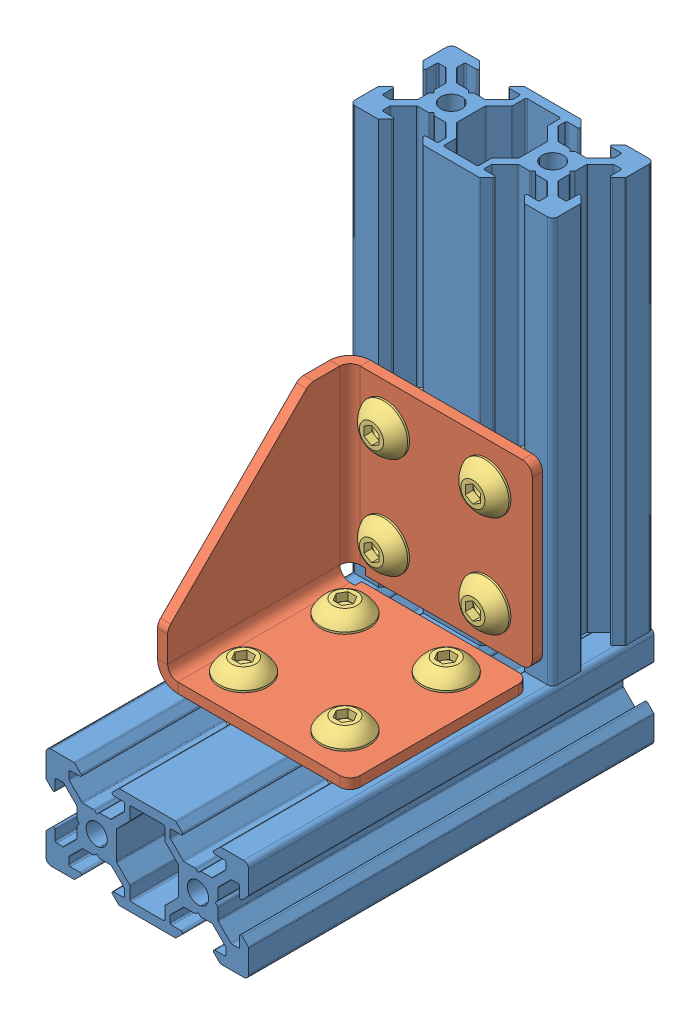
SolidWorks assembly Уголок 20 серия 2х4 40х40х36х2 с перемычкой СБ, configuration По умолчанию. Lengths in mm.
Overall size (40 100 80).
11 component instances, 3 part files, 22 mates.
Components (placement in the parent):
- 204090-1: 204090 [По умолчанию] at origin size (40 20 80)
- 204090-2: 204090 [По умолчанию] at (0 10 10) x (1 0 0) z (0 1 0) size (40 20 80)
- Уголок 20 серия 2х4 40х40х36х2 с перемычкой-1: Уголок 20 серия 2х4 40х40х36х2 с перемычкой [По умолчанию] at (9 10 20) size (38 38 38)
- socket button head screw_iso-1: socket button head screw_iso [ISO 7380 - M5 x 10 - 10N] at (-1 14.75 30) x (0 -1 0) z (0 0 1) size (12.75 9.5 9.5)
- socket button head screw_iso-2: socket button head screw_iso [ISO 7380 - M5 x 10 - 10N] at (-1 14.75 50) x (0 -1 0) z (0 0 1) size (12.75 9.5 9.5)
- socket button head screw_iso-3: socket button head screw_iso [ISO 7380 - M5 x 10 - 10N] at (19 14.75 50) x (0 -1 0) z (0 0 1) size (12.75 9.5 9.5)
- socket button head screw_iso-4: socket button head screw_iso [ISO 7380 - M5 x 10 - 10N] at (19 14.75 30) x (0 -1 0) z (0 0 1) size (12.75 9.5 9.5)
- socket button head screw_iso-5: socket button head screw_iso [ISO 7380 - M5 x 10 - 10N] at (-1 20 24.75) x (0 0 -1) z (1 0 0) size (12.75 9.5 9.5)
- socket button head screw_iso-6: socket button head screw_iso [ISO 7380 - M5 x 10 - 10N] at (-1 40 24.75) x (0 0 -1) z (1 0 0) size (12.75 9.5 9.5)
- socket button head screw_iso-7: socket button head screw_iso [ISO 7380 - M5 x 10 - 10N] at (19 40 24.75) x (0 0 -1) z (1 0 0) size (12.75 9.5 9.5)
- socket button head screw_iso-8: socket button head screw_iso [ISO 7380 - M5 x 10 - 10N] at (19 20 24.75) x (0 0 -1) z (1 0 0) size (12.75 9.5 9.5)
Mates (geometry in assembly coordinates):
- Совпадение1: coincident aligned: plane of 204090-1 through (30 10 80) normal (1 0 0); plane of 204090-2 through (30 90 20) normal (1 0 0)
- Совпадение2: coincident anti-aligned: plane of 204090-1 through (30 10 80) normal (0 1 0); plane of 204090-2 through (0 10 10) normal (0 -1 0)
- Совпадение5: coincident aligned: plane of 204090-1 through (0 0 0) normal (0 0 -1); plane of 204090-2 through (30 90 0) normal (0 0 -1)
- Совпадение6: coincident anti-aligned: plane of 204090-1 through (15.6 10 80) normal (0 1 0); plane of Уголок 20 серия 2х4 40х40х36х2 с перемычкой-1 through (-10 10 58) normal (0 -1 0)
- Совпадение7: coincident anti-aligned: plane of 204090-2 through (15.6 90 20) normal (0 0 1); plane of Уголок 20 серия 2х4 40х40х36х2 с перемычкой-1 through (-10 10 20) normal (0 0 -1)
- Расстояние1: distance = 2 mm aligned: plane of Уголок 20 серия 2х4 40х40х36х2 с перемычкой-1 through (28 10 58) normal (1 0 0); plane of 204090-1 through (30 10 80) normal (1 0 0)
- Концентричный1: concentric aligned: cylinder of Уголок 20 серия 2х4 40х40х36х2 с перемычкой-1 through (-1 12 30) axis (0 1 0) radius 2.75; cylinder of socket button head screw_iso-1 through (-1 14.75 30) axis (0 1 0) radius 4.75
- Совпадение8: coincident anti-aligned: plane of Уголок 20 серия 2х4 40х40х36х2 с перемычкой-1 through (-10 12 58) normal (0 1 0); plane of socket button head screw_iso-1 through (1.5 12 30) normal (0 -1 0)
- Концентричный2: concentric aligned: cylinder of Уголок 20 серия 2х4 40х40х36х2 с перемычкой-1 through (-1 12 50) axis (0 1 0) radius 2.75; cylinder of socket button head screw_iso-2 through (-1 14.75 50) axis (0 1 0) radius 4.75
- Совпадение9: coincident anti-aligned: plane of Уголок 20 серия 2х4 40х40х36х2 с перемычкой-1 through (-10 12 58) normal (0 1 0); plane of socket button head screw_iso-2 through (1.5 12 50) normal (0 -1 0)
- Концентричный3: concentric aligned: cylinder of Уголок 20 серия 2х4 40х40х36х2 с перемычкой-1 through (19 12 50) axis (0 1 0) radius 2.75; cylinder of socket button head screw_iso-3 through (19 14.75 50) axis (0 1 0) radius 4.75
- Совпадение10: coincident anti-aligned: plane of Уголок 20 серия 2х4 40х40х36х2 с перемычкой-1 through (-10 12 58) normal (0 1 0); plane of socket button head screw_iso-3 through (21.5 12 50) normal (0 -1 0)
- Концентричный4: concentric aligned: cylinder of Уголок 20 серия 2х4 40х40х36х2 с перемычкой-1 through (19 12 30) axis (0 1 0) radius 2.75; cylinder of socket button head screw_iso-4 through (19 14.75 30) axis (0 1 0) radius 4.75
- Совпадение11: coincident anti-aligned: plane of Уголок 20 серия 2х4 40х40х36х2 с перемычкой-1 through (-10 12 58) normal (0 1 0); plane of socket button head screw_iso-4 through (21.5 12 30) normal (0 -1 0)
- Концентричный5: concentric aligned: cylinder of Уголок 20 серия 2х4 40х40х36х2 с перемычкой-1 through (-1 20 22) axis (0 0 1) radius 2.75; cylinder of socket button head screw_iso-5 through (-1 20 24.75) axis (0 0 1) radius 4.75
- Совпадение12: coincident anti-aligned: plane of Уголок 20 серия 2х4 40х40х36х2 с перемычкой-1 through (-10 10 22) normal (0 0 1); plane of socket button head screw_iso-5 through (-1 22.5 22) normal (0 0 -1)
- Концентричный6: concentric aligned: cylinder of Уголок 20 серия 2х4 40х40х36х2 с перемычкой-1 through (-1 40 22) axis (0 0 1) radius 2.75; cylinder of socket button head screw_iso-6 through (-1 40 24.75) axis (0 0 1) radius 4.75
- Совпадение13: coincident anti-aligned: plane of Уголок 20 серия 2х4 40х40х36х2 с перемычкой-1 through (-10 10 22) normal (0 0 1); plane of socket button head screw_iso-6 through (-1 42.5 22) normal (0 0 -1)
- Концентричный7: concentric aligned: cylinder of Уголок 20 серия 2х4 40х40х36х2 с перемычкой-1 through (19 40 22) axis (0 0 1) radius 2.75; cylinder of socket button head screw_iso-7 through (19 40 24.75) axis (0 0 1) radius 4.75
- Совпадение14: coincident anti-aligned: plane of Уголок 20 серия 2х4 40х40х36х2 с перемычкой-1 through (-10 10 22) normal (0 0 1); plane of socket button head screw_iso-7 through (19 42.5 22) normal (0 0 -1)
- Концентричный8: concentric aligned: cylinder of Уголок 20 серия 2х4 40х40х36х2 с перемычкой-1 through (19 20 22) axis (0 0 1) radius 2.75; cylinder of socket button head screw_iso-8 through (19 20 24.75) axis (0 0 1) radius 4.75
- Совпадение15: coincident anti-aligned: plane of Уголок 20 серия 2х4 40х40х36х2 с перемычкой-1 through (-10 10 22) normal (0 0 1); plane of socket button head screw_iso-8 through (19 22.5 22) normal (0 0 -1)
